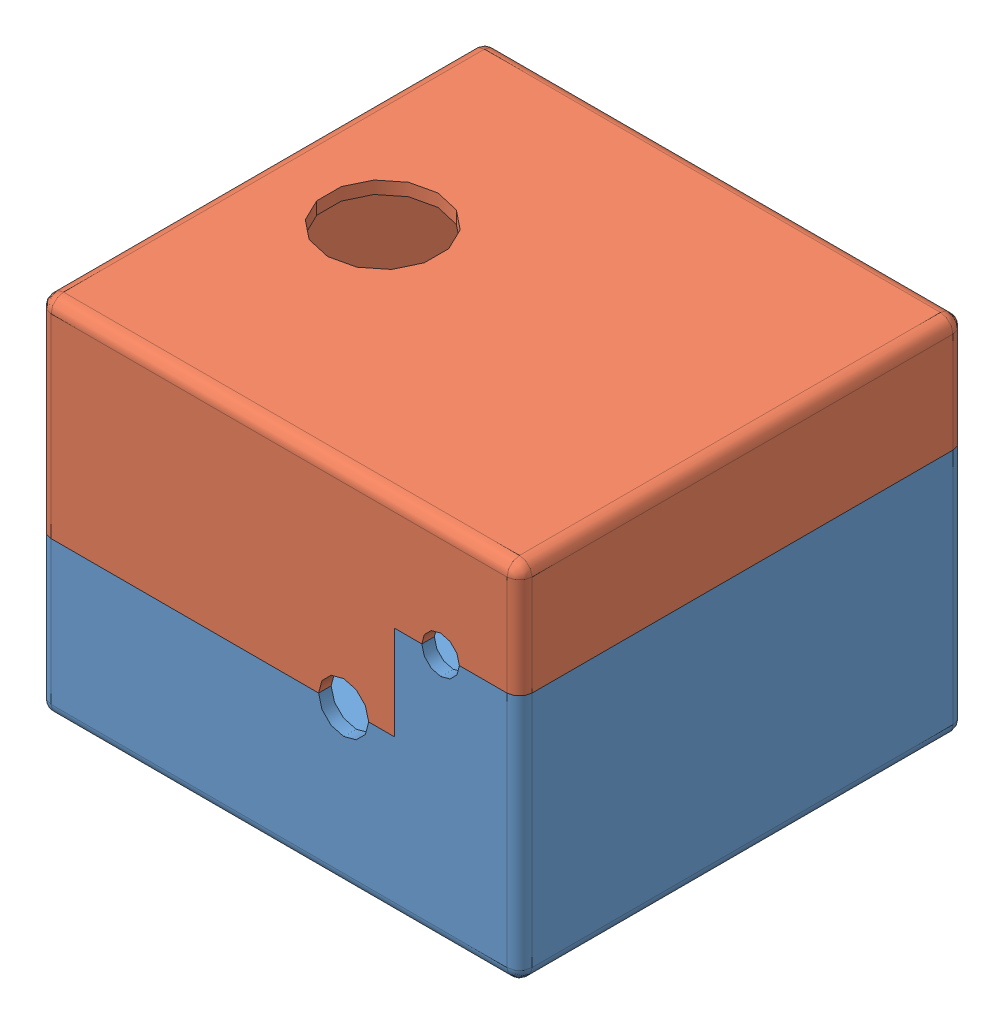
SolidWorks assembly assbyConCaseV2, configuration Default. Lengths in mm.
Overall size (96 72.5 89).
2 component instances, 2 part files, 10 mates.
Components (placement in the parent):
- controller_case_bottom_V3_1212-1: controller_case_bottom_V3_1212 [Default] at (-7.3354 22.9315 28.1282) size (96 49.95 89)
- controller_case_top_V3_1212-2: controller_case_top_V3_1212 [Default] at (-7.3354 95.4315 117.1282) x (1 0 0) z (0 0 -1) size (96 63 89)
Mates (geometry in assembly coordinates):
- Parallel3: parallel: plane of controller_case_bottom_V3_1212-1 through (-7.3354 25.4315 28.1282) normal (0 1 0); plane of controller_case_top_V3_1212-2 through (-7.3354 92.9315 117.435) normal (0 -1 0)
- Coincident7: coincident: plane of controller_case_bottom_V3_1212-1 through (-7.3354 95.4315 28.1282) normal (-1 0 0); plane of controller_case_top_V3_1212-2 through (-7.3354 22.9315 117.435) normal (-1 0 0)
- Parallel4: parallel: plane of controller_case_bottom_V3_1212-1 through (-7.3354 95.4315 117.1282) normal (0 0 1); plane of controller_case_top_V3_1212-2 through (-7.3354 22.9315 117.435) normal (0 0 1)
- Parallel5: parallel: plane of controller_case_bottom_V3_1212-1 through (-7.3354 95.4315 28.1282) normal (0 0 -1); plane of controller_case_top_V3_1212-2 through (-7.3354 22.9315 28.435) normal (0 0 -1)
- Parallel6: parallel: plane of controller_case_bottom_V3_1212-1 through (-7.3354 95.4315 28.1282) normal (-1 0 0); plane of controller_case_top_V3_1212-2 through (-7.3354 22.9315 117.435) normal (-1 0 0)
- Parallel7: parallel: plane of controller_case_bottom_V3_1212-1 through (88.6646 95.4315 28.1282) normal (1 0 0); plane of controller_case_top_V3_1212-2 through (88.6646 22.9315 117.435) normal (1 0 0)
- Coincident12: coincident: plane of controller_case_bottom_V3_1212-1 through (88.6646 72.8815 28.1282) normal (0 1 0); plane of controller_case_top_V3_1212-2 through (88.6646 72.8815 28.435) normal (0 -1 0)
- Coincident13: coincident: plane of controller_case_bottom_V3_1212-1 through (63.6646 54.0915 28.1282) normal (0 1 0); plane of controller_case_top_V3_1212-2 through (63.6646 54.0915 28.435) normal (0 -1 0)
- Coincident14: coincident: plane of controller_case_bottom_V3_1212-1 through (63.6646 32.4315 30.6282) normal (0 1 0); plane of controller_case_top_V3_1212-2 through (21.6646 32.4315 30.935) normal (0 -1 0)
- Distance1: distance = 0 mm aligned: plane of controller_case_top_V3_1212-2 through (-7.3354 22.9315 28.1282) normal (0 0 -1); plane of controller_case_bottom_V3_1212-1 through (-7.3354 95.4315 28.1282) normal (0 0 -1)
